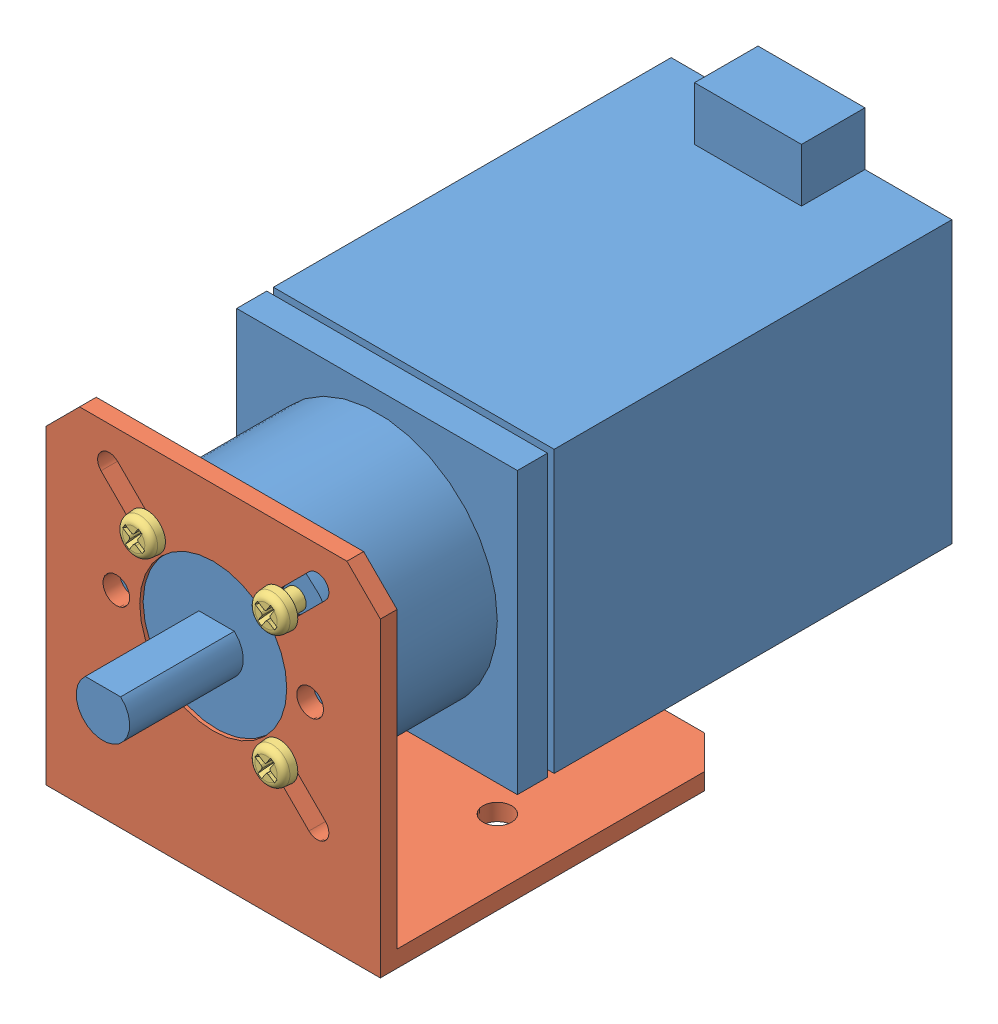
SolidWorks assembly 装配体1^摩擦系数测量, configuration 默认. Lengths in mm.
Overall size (50 59.5 106).
6 component instances, 3 part files, 11 mates.
Components (placement in the parent):
- 42减速电机-减速比5.18-1: 42减速电机-减速比5.18 [默认] at (22.662 20.8247 -53) size (42 50 106)
- 42减速电机支架-1: 42减速电机支架 [默认] at (22.662 16.0747 36.5) x (-1 0 0) z (0 0 -1) size (50 51.5 53.5)
- cross recessed cheese head screws gb-4: cross recessed cheese head screws gb [GB_CROSS_SCREWS_TYPE2 M3X8-8  H type-N] at (32.5615 30.7242 38.5) x (0 0 -1) z (0.543579 0.839358 0) size (10.01 5.5 5.5)
- cross recessed cheese head screws gb-5: cross recessed cheese head screws gb [GB_CROSS_SCREWS_TYPE2 M3X8-8  H type-N] at (12.7625 10.9252 38.5) x (0 0 -1) z (0.543579 0.839358 0) size (10.01 5.5 5.5)
- cross recessed cheese head screws gb-6: cross recessed cheese head screws gb [GB_CROSS_SCREWS_TYPE2 M3X8-8  H type-N] at (12.7625 30.7242 38.5) x (0 0 -1) z (0.543579 0.839358 0) size (10.01 5.5 5.5)
- cross recessed cheese head screws gb-7: cross recessed cheese head screws gb [GB_CROSS_SCREWS_TYPE2 M3X8-8  H type-N] at (32.5615 10.9252 38.5) x (0 0 -1) z (0.543579 0.839358 0) size (10.01 5.5 5.5)
Mates (geometry in assembly coordinates):
- 重合1: coincident anti-aligned: plane of 42减速电机-减速比5.18-1 through (22.662 20.8247 34) normal (0 0 1); plane of 42减速电机支架-1 through (22.662 16.0747 34) normal (0 0 -1)
- 同心1: concentric anti-aligned: circle of 42减速电机-减速比5.18-1; circle of 42减速电机支架-1
- 平行1: parallel aligned: plane of 42减速电机-减速比5.18-1 through (1.662 41.8247 12) normal (0 1 0); plane of 42减速电机支架-1 through (47.662 -7.1753 -120.5625) normal (0 1 0)
- 重合9: coincident anti-aligned: plane of cross recessed cheese head screws gb-4 through (31.0506 31.7027 36.5) normal (0 0 -1); plane of 42减速电机支架-1 through (22.662 16.0747 36.5) normal (0 0 1)
- 重合10: coincident aligned: plane of cross recessed cheese head screws gb-4 through (31.0506 31.7027 36.5) normal (0 0 -1); circle of cross recessed cheese head screws gb-6
- 重合11: coincident aligned: plane of cross recessed cheese head screws gb-6 through (11.2516 31.7027 36.5) normal (0 0 -1); plane of cross recessed cheese head screws gb-7 through (31.0506 11.9037 36.5) normal (0 0 -1)
- 重合12: coincident aligned: plane of cross recessed cheese head screws gb-5 through (11.2516 11.9037 36.5) normal (0 0 -1); plane of cross recessed cheese head screws gb-7 through (31.0506 11.9037 36.5) normal (0 0 -1)
- 同心6: concentric anti-aligned: circle of 42减速电机-减速比5.18-1; circle of cross recessed cheese head screws gb-6
- 同心7: concentric anti-aligned: circle of 42减速电机-减速比5.18-1; circle of cross recessed cheese head screws gb-4
- 同心8: concentric anti-aligned: circle of 42减速电机-减速比5.18-1; circle of cross recessed cheese head screws gb-7
- 同心9: concentric anti-aligned: circle of 42减速电机-减速比5.18-1; circle of cross recessed cheese head screws gb-5
